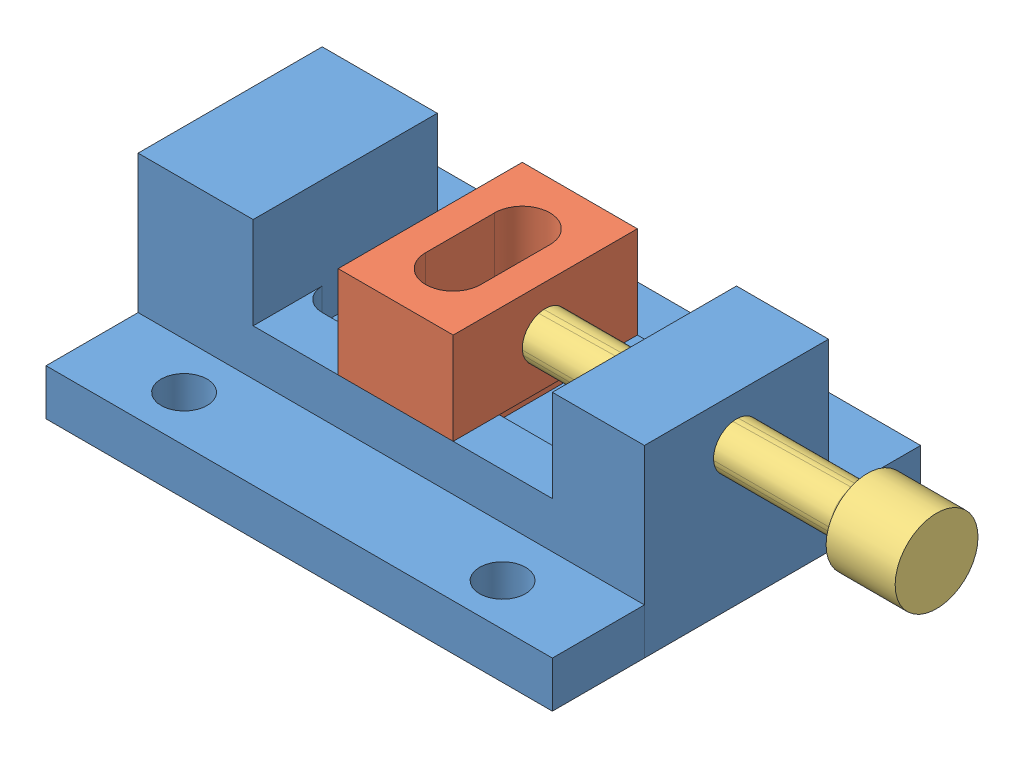
SolidWorks assembly vise, configuration ﾃﾞﾌｫﾙﾄ. Lengths in mm.
Overall size (153.46 42.71 80).
4 component instances, 4 part files, 12 mates.
Components (placement in the parent):
- vise_01-1: vise_01 [ﾃﾞﾌｫﾙﾄ] at (-25 -20 0) x (1 0 0) z (0 -1 0) size (110 80 40)
- vise_02-1: vise_02 [ﾃﾞﾌｫﾙﾄ] at (18.4634 0 0) size (25 26 40)
- vise_03-1: vise_03 [ﾃﾞﾌｫﾙﾄ] at (43.4634 10 0) x (1 0 0) z (0 -0.740795 -0.671731) size (99 18 18)
- HNT3-ST-M5-1: HNT3-ST-M5 [HNT3-ST-M5] at (33.2634 10 0) x (0 -0.624018 0.78141) z (1 0 0) size (8 9.24 3.2)
Mates (geometry in assembly coordinates):
- Coincident2: coincident aligned: plane of vise_01-1 through (-25 -20 0) normal (0 0 1)
- Coincident6: coincident aligned: plane of vise_02-1 through (18.4634 0 0) normal (0 0 1)
- Coincident9: coincident aligned: plane of vise_01-1 through (0 30.3852 -20.01) normal (1 0 0)
- Coincident12: coincident aligned: plane of vise_01-1 through (0 0 -20.01) normal (0 1 0)
- Coincident13: coincident aligned: plane of vise_02-1 through (18.4634 0 0) normal (0 1 0)
- Coincident14: coincident anti-aligned: line of vise_03-1 through (70 113.4634 10) axis (0 -1 0)
- Coincident15: coincident aligned: line of HNT3-ST-M5-1 through (35.2935 10 0) axis (1 0 0)
- Coincident17: coincident anti-aligned: plane of vise_02-1 through (43.4634 0 20) normal (1 0 0); plane of vise_03-1 through (43.4634 10 0) normal (-1 0 0)
- Coincident18: coincident anti-aligned: plane of vise_03-1 through (36.4634 10 0) normal (-1 0 0); plane of HNT3-ST-M5-1 through (36.4634 5.0079 6.2513) normal (1 0 0)
- LimitDistance1: limit distance = 18.4634 mm anti-aligned: plane of vise_01-1 through (0 30.3852 -20.01) normal (1 0 0); plane of vise_02-1 through (18.4634 0 20) normal (-1 0 0)
- Coincident19: coincident anti-aligned: plane of vise_01-1 through (0 30.3852 -20.01) normal (1 0 0); plane of vise_02-1 through (0 0 20) normal (-1 0 0)
- Coincident20: coincident: plane of vise_01-1 through (65 0 -20.01) normal (-1 0 0); plane of vise_02-1 through (25 0 20) normal (1 0 0)
